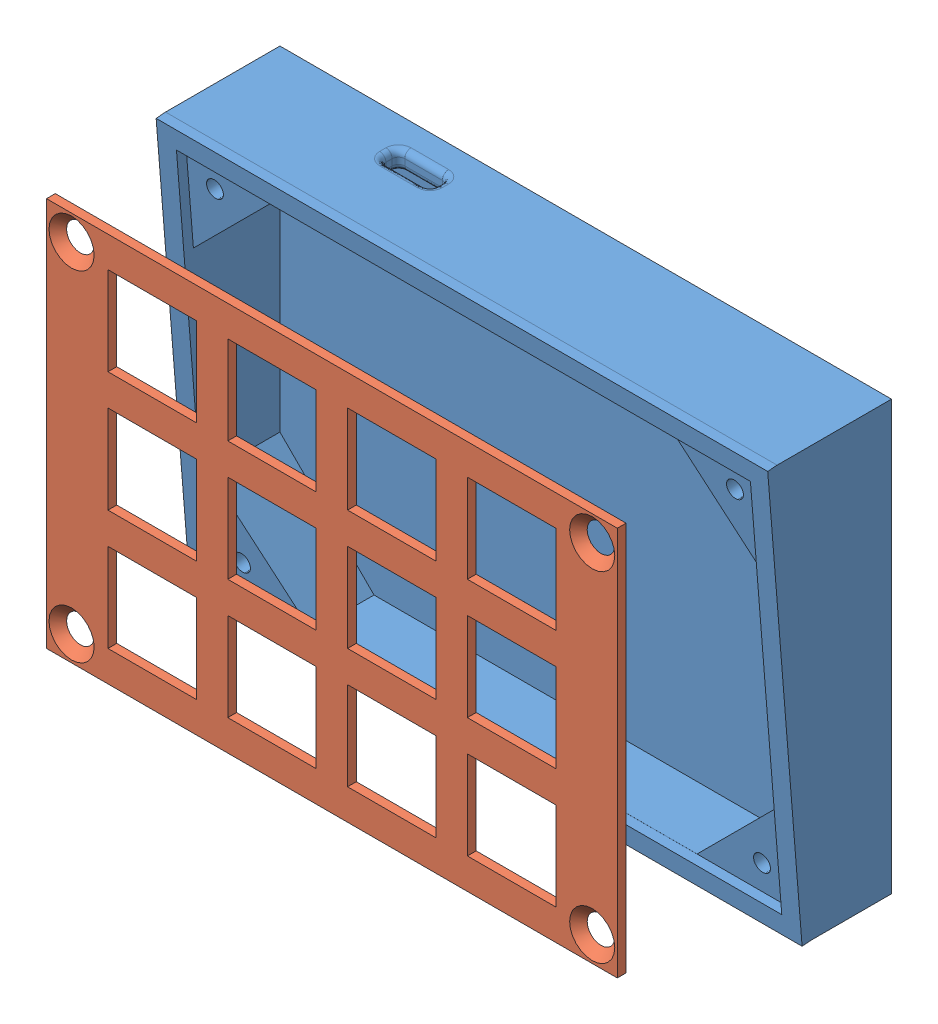
SolidWorks assembly cans12er, configuration Standard. Lengths in mm.
Overall size (97.5 70.59 41.85).
2 component instances, 2 part files, 1 mates.
Components (placement in the parent):
- bottom-1: bottom [Standard] at (-38.8195 -80.0928 67.9056) size (97.5 68.42 19.74)
- top-1: top [Standard] at (-1084.6436 758.1022 95.3534) size (91 62.1 1.4)
Mates (geometry in assembly coordinates):
- Parallel1: parallel: plane of assembly; plane of assembly; plane of bottom-1 through (52.6805 -80.0928 54.9056) normal (0 0 -1); plane of top-1 through (-1084.6436 758.1022 95.3534) normal (0 0 -1)
